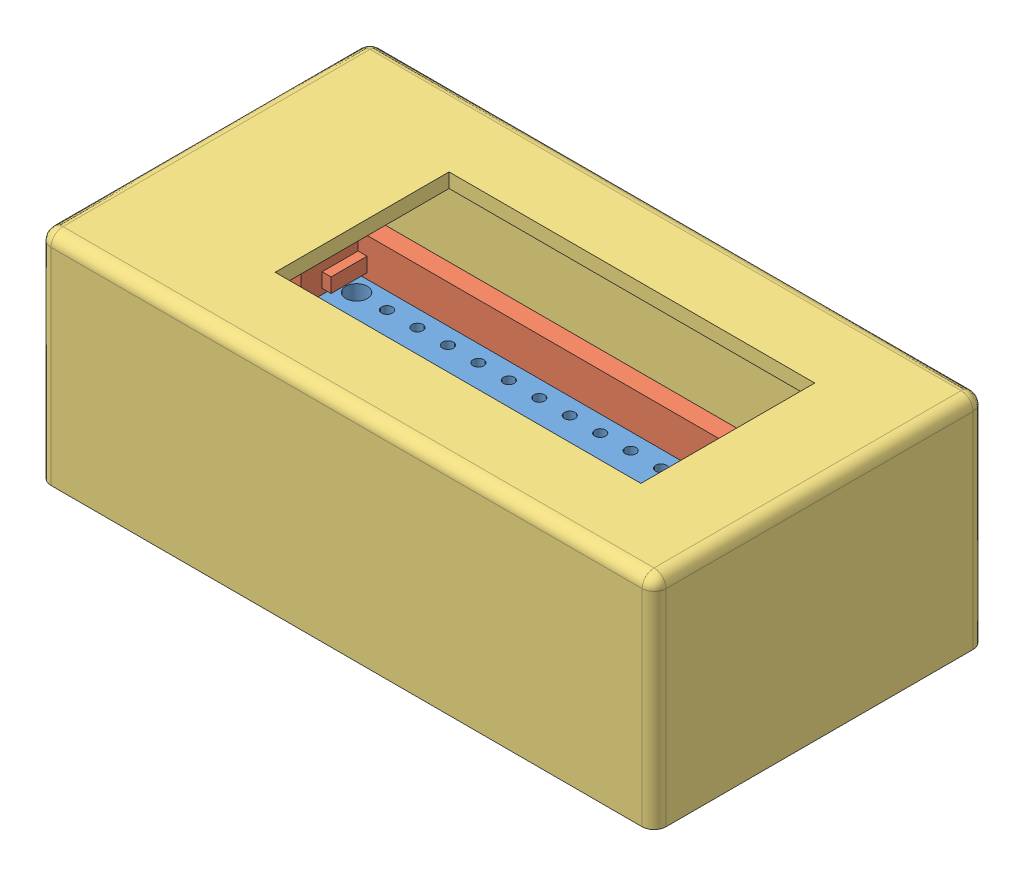
SolidWorks assembly Assem1, configuration Default. Lengths in mm.
Overall size (51.3 19.5 27.6).
5 component instances, 5 part files, 12 mates.
Components (placement in the parent):
- arduino nano_nopins-1: arduino nano_nopins [Default] at (26.4457 -22.8077 21.3319) x (-1 0 0) z (0 0 1) size (45 7.35 18)
- casing-part1-1: casing-part1 [Default] at (-13.1837 -26.9077 22.9374) size (47 8.2 23.5)
- Display TM1637-1: Display TM1637 [По умолчанию] at (9.2974 -15.4077 13.8307) x (-1 0 0) z (0 1 0) size (45 22 11) (hidden)
- casing-part2-1: casing-part2 [Default] at (-14.7526 -11.1077 1.8807) x (1 0 0) z (0 0 -1) size (51.3 18.2 27.6)
- button-1: button [Default] at (13.3234 -26.6577 13.6874) x (0.003563 0 -0.999994) z (-0.999994 0 -0.003563) size (7 2.75 3)
Mates (geometry in assembly coordinates):
- Parallel1: parallel anti-aligned: plane of arduino nano_nopins-1 through (26.4457 -24.4077 21.3319) normal (0 -1 0); plane of assembly through (0 0 0) normal (0 1 0)
- Parallel4: parallel anti-aligned: plane of arduino nano_nopins-1 through (-12.9343 -24.4077 4.7119) normal (-1 0 0); plane of assembly through (0 0 0) normal (1 0 0)
- Distance3: distance = 0.1 mm anti-aligned: plane of arduino nano_nopins-1 through (-12.9343 -24.4077 4.7119) normal (-1 0 0); plane of casing-part1-1 through (-13.1837 -19.9077 22.9374) normal (1 0 0)
- Parallel7: parallel aligned: plane of Display TM1637-1 through (9.2974 -14.1077 13.8307) normal (0 1 0); plane of assembly through (0 0 0) normal (0 1 0)
- Parallel5: parallel aligned: plane of Display TM1637-1 through (31.7974 -14.1077 2.8307) normal (1 0 0); plane of assembly through (0 0 0) normal (1 0 0)
- Coincident6: coincident anti-aligned: plane of Display TM1637-1 through (9.2974 -14.1077 13.8307) normal (0 1 0); line of casing-part2-1 through (-7.7526 -14.1077 25.4807) axis (-1 0 0)
- Distance1: distance = 0.1 mm anti-aligned: plane of casing-part2-1 through (26.8974 -1.1077 20.9307) normal (0 0 -1); plane of Display TM1637-1 through (-3.2026 -6.9077 20.8307) normal (0 0 1)
- Distance2: distance = 0.1 mm anti-aligned: plane of casing-part2-1 through (26.8974 -1.1077 6.4307) normal (-1 0 0); plane of Display TM1637-1 through (26.7974 -6.9077 6.8307) normal (1 0 0)
- Coincident14: coincident anti-aligned: plane of arduino nano_nopins-1 through (26.4457 -24.4077 21.3319) normal (0 -1 0); plane of casing-part1-1 through (-13.1837 -24.4077 22.9374) normal (0 1 0)
- Coincident15: coincident aligned: plane of casing-part1-1 through (-13.1837 -28.1077 22.9374) normal (0 -1 0); plane of casing-part2-1 through (-14.7526 -28.1077 1.8807) normal (0 -1 0)
- Coincident16: coincident anti-aligned: plane of casing-part1-1 through (-13.1837 -26.9077 22.9374) normal (0 1 0); plane of button-1 through (13.3234 -26.9077 13.6874) normal (0 -1 0)
- Concentric2: concentric anti-aligned: cylinder of casing-part1-1 through (13.3163 -19.9077 15.6874) axis (0 -1 0) radius 1.25; cylinder of button-1 through (13.3163 -29.4077 15.6874) axis (0 1 0) radius 1
